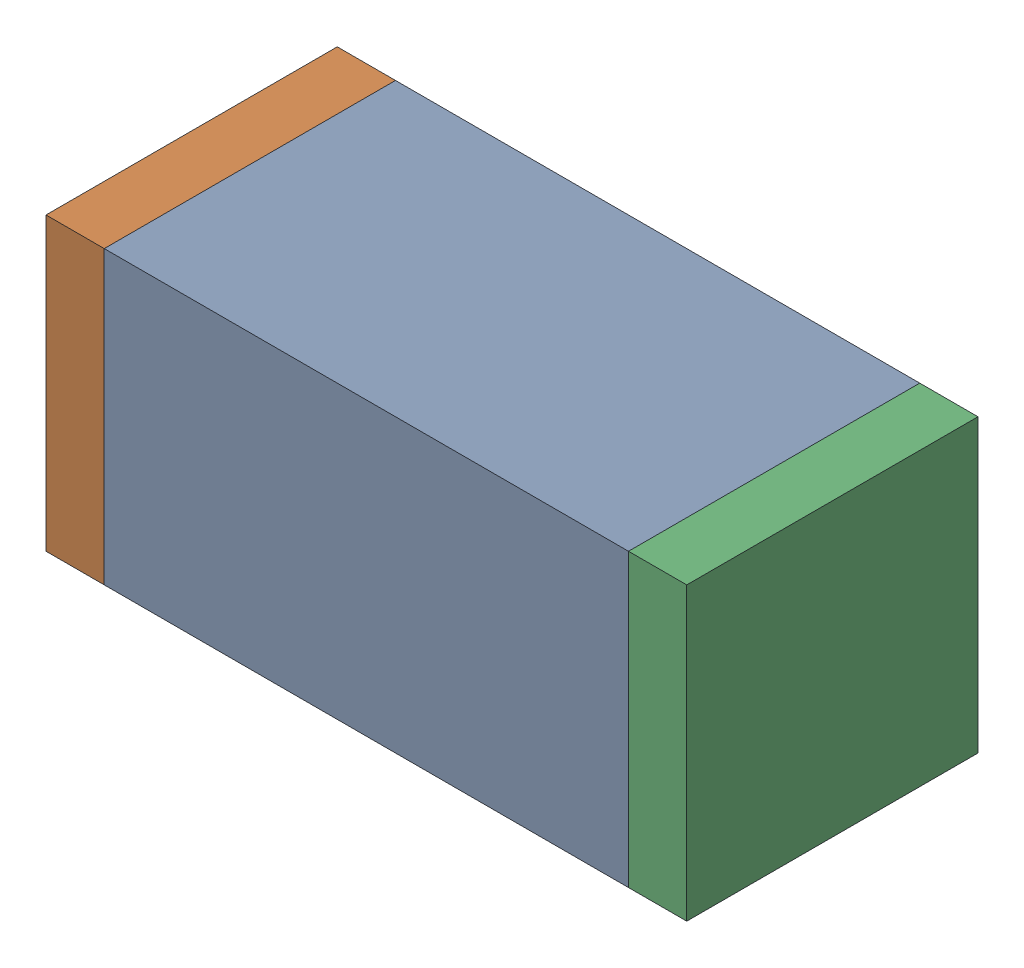
SolidWorks assembly C37, configuration Default. Lengths in mm.
Overall size (1.1 0.5 0.5).
6 component instances, 2 part files, 0 mates.
Components (placement in the parent):
- 836749680-1: 836749680 [Default] at (125 32.2 0) size (0.9 0.5 0.5)
  - Extruded_4-1: Extruded_4 [Default] at origin size (0.9 0.5 0.5)
- 810156080-1: 810156080 [Default] at (124.5 32.2 0) size (0.1 0.5 0.5)
  - Extruded_5-1: Extruded_5 [Default] at origin size (0.1 0.5 0.5)
- 810156080-2: 810156080 [Default] at (125.5 32.2 0) size (0.1 0.5 0.5)
  - Extruded_5-1: Extruded_5 [Default] at origin size (0.1 0.5 0.5)
